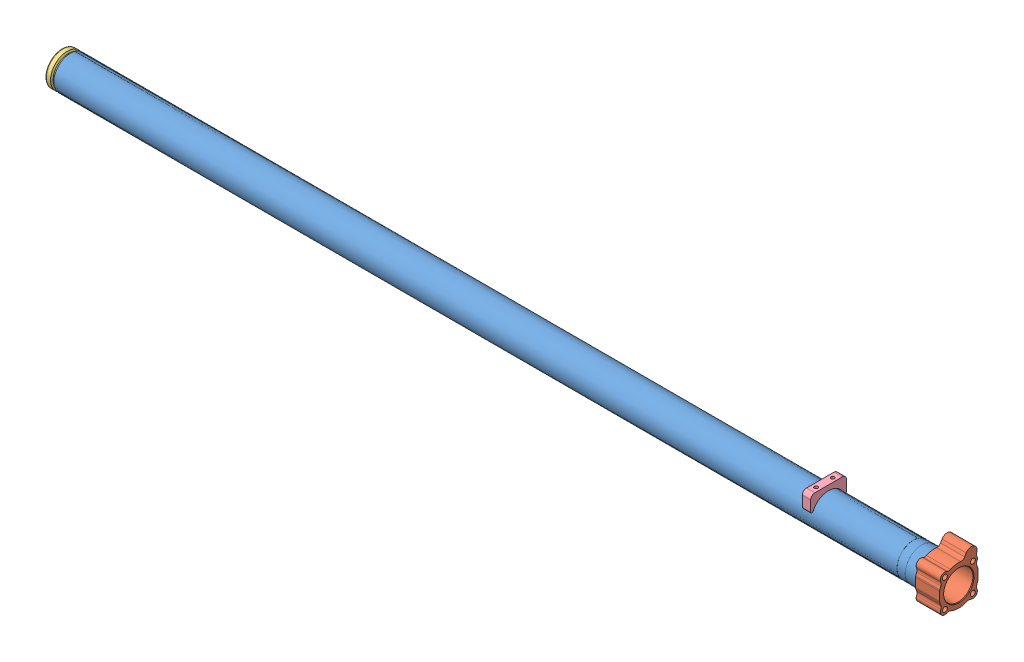
SolidWorks assembly 6344575, configuration Default. Lengths in mm.
Overall size (2170 113.03 92).
4 component instances, 4 part files, 12 mates.
Components (placement in the parent):
- 6344576-1: 6344576 [Default] at (-2137 0 0) x (-1 0 0) z (0 0 -1) size (2081 80 80)
- 6344547-1: 6344547 [Default] at (1 0 0) x (0 0 1) z (-1 0 0) size (92 113.03 58)
- 6344587-1: 6344587 [Default] at (-2135 0 0) x (-1 0 0) z (0 0 -1) size (35 80 80)
- 6304256-1: 6304256 [Default] at (-323 0 0) x (0 0 1) z (1 0 0) size (86 38.4 20)
Mates (geometry in assembly coordinates):
- Coincident11: coincident aligned: plane of 6344547-1 through (0 90 0) normal (1 0 0); plane of assembly through (0 0 0) normal (1 0 0)
- Concentric4: concentric aligned: cylinder of 6344576-1 through (-2014.2158 0 0) axis (1 0 0) radius 40; cylinder of 6344547-1 through (-59 0 0) axis (1 0 0) radius 47.5
- Concentric5: concentric: cylinder of 6344547-1 through (-59 0 0) axis (1 0 0) radius 47.5
- Coincident12: coincident anti-aligned: plane of 6344576-1 through (-56 37.5 0) normal (1 0 0); plane of 6344547-1 through (-56 37.5 0) normal (-1 0 0)
- Parallel6: parallel aligned: plane of 6344547-1 through (1 0 0) normal (0 0 1); plane of assembly through (0 0 0) normal (0 0 1)
- Parallel7: parallel anti-aligned: plane of 6344576-1 through (-2137 0 0) normal (0 0 -1); plane of assembly through (0 0 0) normal (0 0 1)
- Concentric6: concentric aligned: cylinder of 6344576-1 through (-2014.2158 0 0) axis (1 0 0) radius 35; cylinder of 6344587-1 through (-2103.7231 0 0) axis (1 0 0) radius 36
- Coincident16: coincident anti-aligned: plane of 6344576-1 through (-2137 35 0) normal (-1 0 0); plane of 6344587-1 through (-2137 36 0) normal (1 0 0)
- Coincident17: coincident anti-aligned: plane of 6344587-1 through (-2135 0 0) normal (0 0 -1); plane of assembly through (0 0 0) normal (0 0 1)
- Concentric7: concentric anti-aligned: cylinder of 6344576-1 through (-2014.2158 0 0) axis (1 0 0) radius 40; cylinder of 6304256-1 through (-313 0 0) axis (-1 0 0) radius 40.5
- Distance4: distance = 265 mm anti-aligned: plane of 6344547-1 through (-58 37.5 0) normal (-1 0 0); plane of 6304256-1 through (-323 0 0) normal (1 0 0)
- Parallel8: parallel anti-aligned: plane of 6304256-1 through (-323 0 0) normal (0 -1 0); plane of assembly through (0 0 0) normal (0 1 0)
